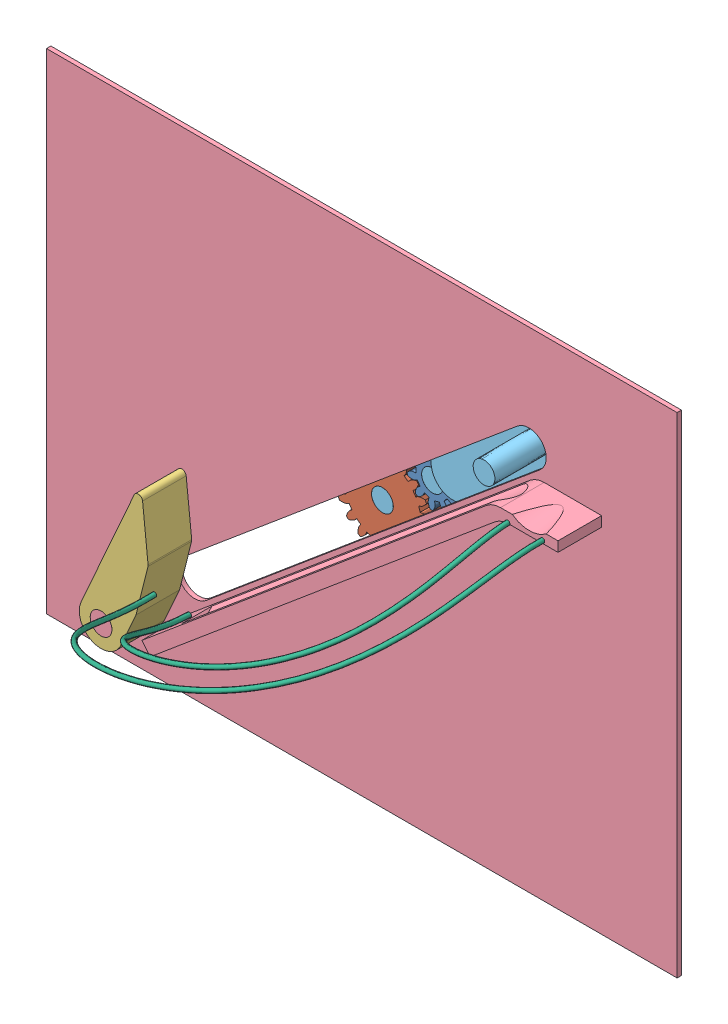
SolidWorks assembly gear_transfer, configuration 預設. Lengths in mm.
Overall size (144.6 112.28 114.63).
11 component instances, 7 part files, 23 mates.
Components (placement in the parent):
- 10_gear-1: 10_gear [預設] at (23.1771 39.6418 -114.1732) x (-0.21124 -0.977434 0) z (0 0 1) size (11.89 11.93 5)
- 20_gear-1: 20_gear [預設] at (11.6864 30 -114.1732) x (0.562704 0.826659 0) z (0 0 1) size (21.96 21.96 5)
- ball_stop-1: ball_stop [預設] at (-12.8239 19.8956 -103.1732) x (0.898844 0.43827 0) z (0 0 1) size (26.36 28.3 10)
- board-1: board [預設] at (-59.3385 -25.1153 -104.1732) size (144.6 112.28 11.89)
- gear_shaft-1: gear_shaft [push] at (30.8375 46.0697 -109.1732) x (0.766044 0.642788 0) z (0 0 1) size (35 10 15)
- rail-2-1: rail-2 [預設] at (-19.9847 1.7371 -92.5758) size (90.01 56.41 45.03)
- motor-1: motor [預設] at (11.6864 5 -122.1732) x (0 0 -1) z (1 0 0) size (45 54 20)
- gear_shaft-2: gear_shaft [預設] at (11.6864 30 -117.1732) x (0.766044 0.642788 0) z (0 0 1) size (35 10 8)
- 10_gear-2: 10_gear [預設] at (30.8375 46.0697 -114.1732) x (0.324864 -0.945761 0) z (0 0 1) size (11.89 11.93 5)
- 10_gear-3: 10_gear [預設] at (11.6864 30 -122.1732) size (11.89 11.93 5)
- 20_gear-2: 20_gear [預設] at (11.6864 15 -117.1732) x (-0.999982 -0.00605 0) z (0 0 -1) size (21.96 21.96 5)
Mates (geometry in assembly coordinates):
- 同軸心1: concentric aligned: cylinder of 20_gear-1 through (11.6864 30 -109.1732) axis (0 0 -1) radius 2.5; cylinder of gear_shaft-2 through (11.6864 30 -109.1732) axis (0 0 -1) radius 2.5
- 同軸心2: concentric aligned: cylinder of 10_gear-1 through (23.1771 39.6418 -109.1732) axis (0 0 -1) radius 2.5; cylinder of gear_shaft-2 through (23.1771 39.6418 -109.1732) axis (0 0 -1) radius 2.5
- 同軸心3: concentric aligned: cylinder of gear_shaft-2 through (30.8375 46.0697 -109.1732) axis (0 0 -1) radius 2.5; cylinder of 10_gear-2 through (30.8375 46.0697 -109.1732) axis (0 0 -1) radius 2.5
- 重合/共線/共點1: coincident anti-aligned: plane of 20_gear-1 through (11.6864 30 -114.1732) normal (0 0 -1); plane of gear_shaft-2 through (11.6864 30 -114.1732) normal (0 0 1)
- 重合/共線/共點2: coincident anti-aligned: plane of 10_gear-1 through (23.1771 39.6418 -114.1732) normal (0 0 -1); plane of gear_shaft-2 through (11.6864 30 -114.1732) normal (0 0 1)
- 重合/共線/共點3: coincident anti-aligned: plane of gear_shaft-2 through (11.6864 30 -114.1732) normal (0 0 1); plane of 10_gear-2 through (30.8375 46.0697 -114.1732) normal (0 0 -1)
- 同軸心4: concentric anti-aligned: cylinder of motor-1 through (11.6864 15 -117.1732) axis (0 0 -1) radius 3; cylinder of 20_gear-2 through (11.6864 15 -122.1732) axis (0 0 1) radius 2.5
- 重合/共線/共點4: coincident anti-aligned: plane of motor-1 through (21.6864 -15 -122.1732) normal (0 0 1); plane of 20_gear-2 through (11.6864 15 -122.1732) normal (0 0 -1)
- 平行相距3: distance = 15 mm anti-aligned: plane of motor-1 through (21.6864 -15 -122.1732) normal (0 -1 0); plane of assembly through (0 0 0) normal (0 1 0)
- 重合/共線/共點12: coincident anti-aligned: plane of motor-1 through (21.6864 -15 -122.1732) normal (0 0 1); plane of 10_gear-3 through (11.6864 30 -122.1732) normal (0 0 -1)
- 鎖住1: lock: unknown of motor-1; unknown of 10_gear-3
- 重合/共線/共點15: coincident anti-aligned: circle of gear_shaft-2; cylinder of 10_gear-3 through (11.6864 30 -117.1732) axis (0 0 -1) radius 2.5
- 重合/共線/共點16: coincident anti-aligned: plane of gear_shaft-2 through (11.6864 30 -117.1732) normal (0 0 -1); plane of 10_gear-3 through (11.6864 30 -117.1732) normal (0 0 1)
- 同軸心6: concentric aligned: circle of gear_shaft-1; circle of gear_shaft-2
- 重合/共線/共點19: coincident anti-aligned: plane of gear_shaft-1 through (30.8375 46.0697 -109.1732) normal (0 0 -1); plane of 10_gear-2 through (30.8375 46.0697 -109.1732) normal (0 0 1)
- 齒輪結合7: gear = 1 : 2 mm: circle of 20_gear-1; circle of 10_gear-1
- 齒輪結合8: gear = 5 : 5 mm: circle of 10_gear-1; circle of 10_gear-2
- 鎖住3: lock: unknown of gear_shaft-1; unknown of gear_shaft-2
- 平行(R)4: parallel anti-aligned: plane of board-1 through (-27.9097 1.9489 -103.1732) normal (0.642788 -0.766044 0); plane of gear_shaft-1 through (27.6236 49.8999 -106.1732) normal (-0.642788 0.766044 0)
- 平行(R)5: parallel aligned: plane of board-1 through (-59.3385 -25.1153 -103.1732) normal (0 -1 0); plane of motor-1 through (21.6864 -15 -122.1732) normal (0 -1 0)
- 平行相距4: distance = 2 mm anti-aligned: plane of board-1 through (-59.3385 -25.1153 -104.1732) normal (0 0 -1); plane of gear_shaft-1 through (30.8375 46.0697 -106.1732) normal (0 0 1)
- 同軸心7: concentric aligned: cylinder of ball_stop-1 through (-36.8292 -10.7571 -93.1732) axis (0 0 -1) radius 2.5; cylinder of board-1 through (-36.8292 -10.7571 -93.1732) axis (0 0 -1) radius 2.5
- 重合/共線/共點25: coincident anti-aligned: plane of ball_stop-1 through (-36.8292 -10.7571 -103.1732) normal (0 0 -1); plane of board-1 through (-59.3385 -25.1153 -103.1732) normal (0 0 1)
